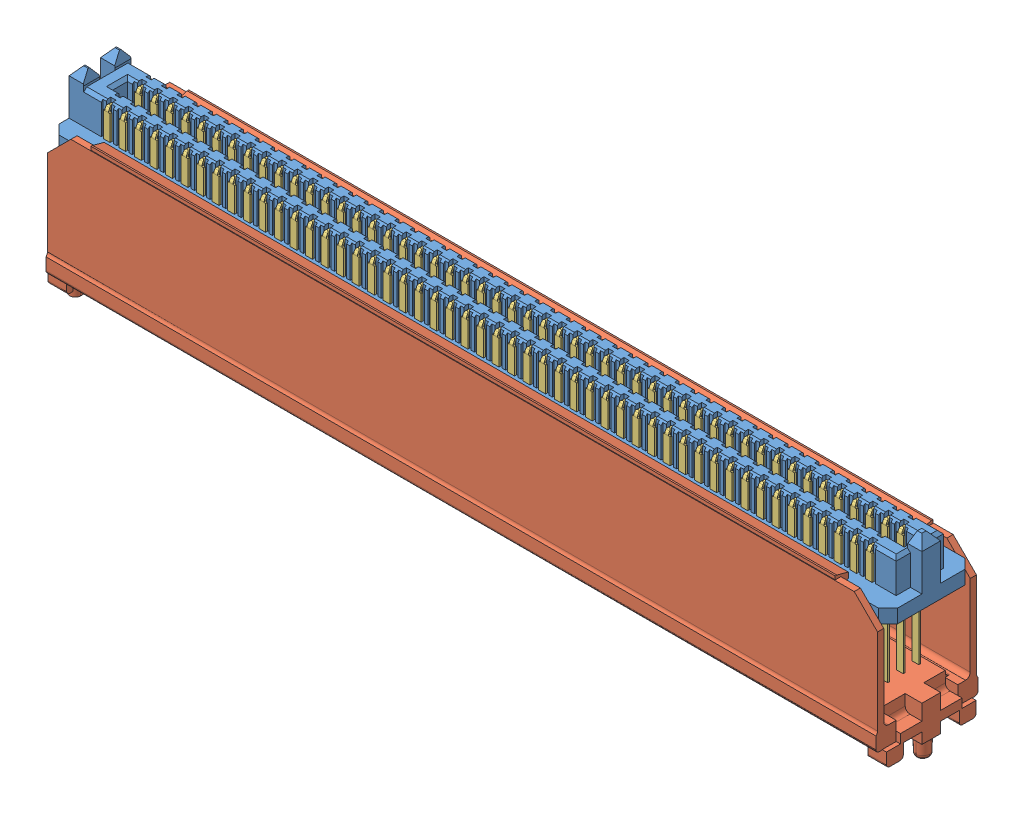
SolidWorks assembly SEAM_50_11_0_L_04_2_A_K_TR, configuration Default. Lengths in mm.
Overall size (68.48 15.88 8.33).
5 component instances, 5 part files, 0 mates.
Components (placement in the parent):
- _SEAM_50_11_0_L_04_1_A_K_TR_body_2-1: _SEAM_50_11_0_L_04_1_A_K_TR_body_2 [Default] at origin size (68.48 6.35 7.06)
- _SEAM_50_11_0_L_04_1_A_K_TR_spacer_4-1: _SEAM_50_11_0_L_04_1_A_K_TR_spacer_4 [Default] at origin size (68.48 13.13 8.33)
- _SEAM_50_11_0_L_04_1_A_K_TR_conn_6-1: _SEAM_50_11_0_L_04_1_A_K_TR_conn_6 [Default] at origin size (67.97 13.3 6.55)
- _SEAM_K_Pad_04_8-1: _SEAM_K_Pad_04_8 [Default] at (0 2.6924 0) size (5.99 0.13 5.99) (hidden)
- _SEAM_Triangle_10-1: _SEAM_Triangle_10 [Default] at (32.2834 1.2954 -1.6764) x (-1 0 0) z (0 0 -1) size (1.02 1.27 0.13)
